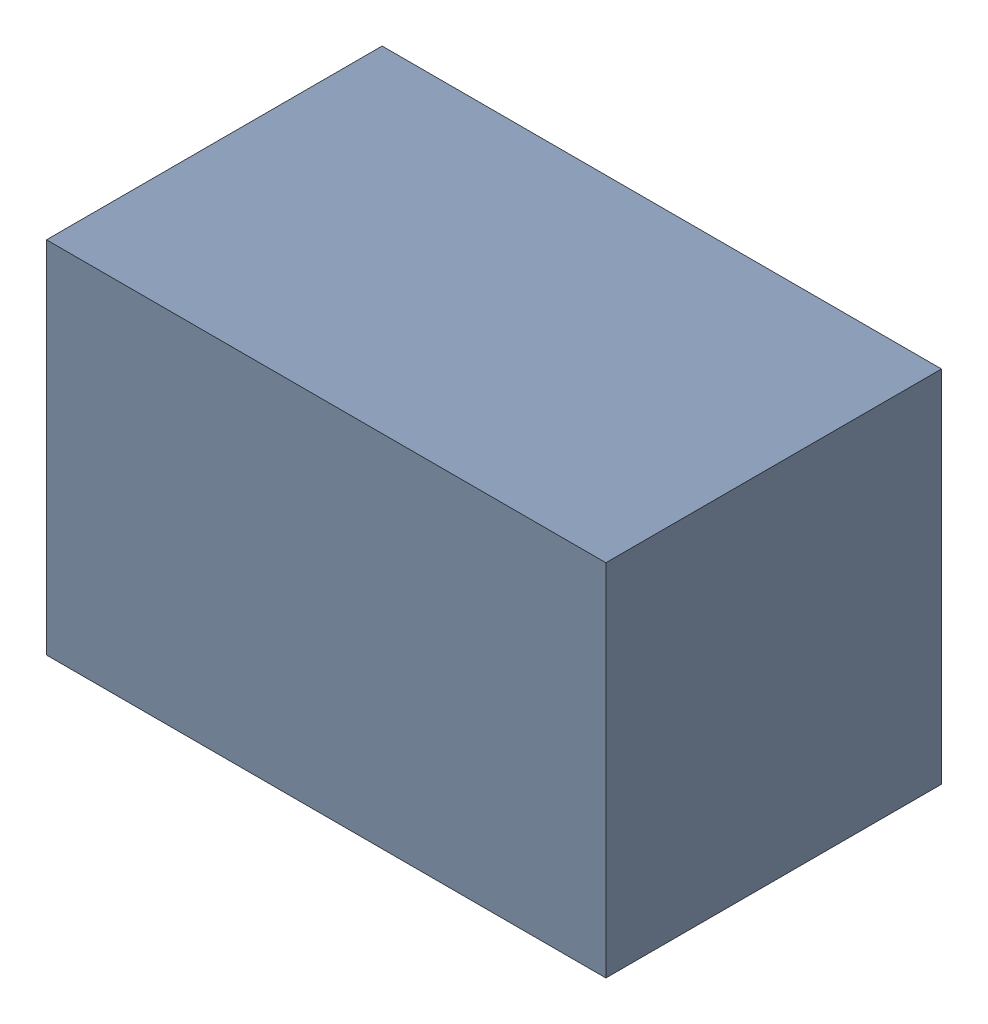
SolidWorks assembly C22, configuration Default. Lengths in mm.
Overall size (2.1 1.35 1.26).
2 component instances, 1 part files, 0 mates.
Components (placement in the parent):
- 407985824-1: 407985824 [Default] at (50.546 49.276 0.0127) size (2.1 1.35 1.26)
  - Extruded_2-1: Extruded_2 [Default] at origin size (2.1 1.35 1.26)
